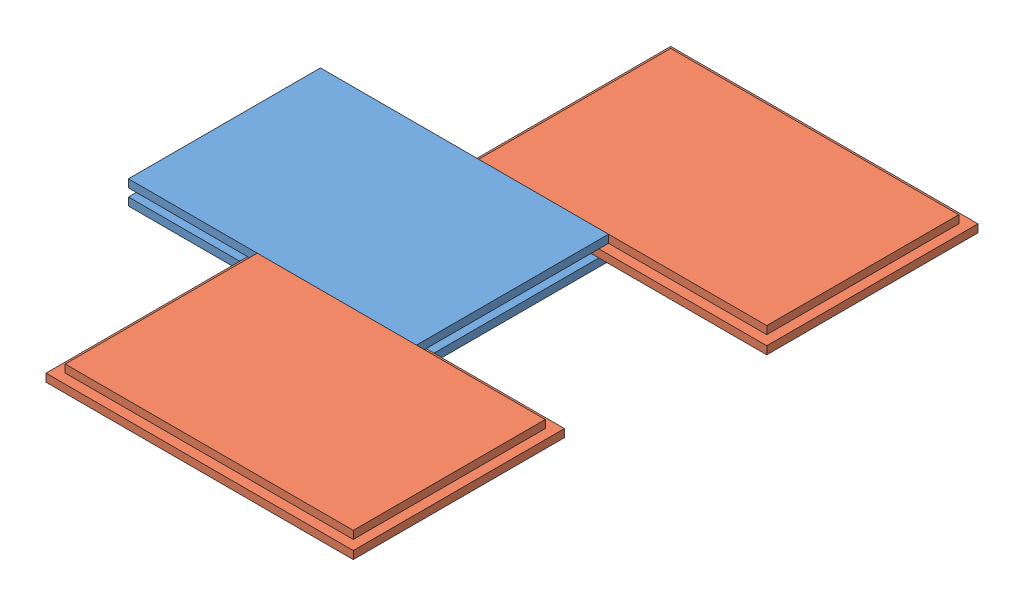
SolidWorks assembly Assem1, configuration Default. Lengths in mm.
Overall size (237.4 12.3 310).
3 component instances, 2 part files, 4 mates.
Components (placement in the parent):
- foto lijst met gleuf concept 1-1: foto lijst met gleuf concept 1 [Default] at (22.8023 87.9306 121.9151) size (150 12.3 100)
- foto lijst met uitstekels concept 1-1: foto lijst met uitstekels concept 1 [Default] at (89.8868 87.9306 221.9151) size (160 12.3 110)
- foto lijst met uitstekels concept 1-2: foto lijst met uitstekels concept 1 [Default] at (105.2056 87.9306 21.9151) size (160 12.3 110)
Mates (geometry in assembly coordinates):
- Coincident1: coincident: plane of foto lijst met gleuf concept 1-1 through (22.8023 96.1306 121.9151) normal (0 -1 0); plane of foto lijst met uitstekels concept 1-1 through (89.8868 96.1306 221.9151) normal (0 1 0)
- Coincident2: coincident: plane of foto lijst met gleuf concept 1-1 through (-52.1977 100.2306 171.9151) normal (0 0 1); plane of foto lijst met uitstekels concept 1-1 through (14.8868 100.2306 171.9151) normal (0 0 -1)
- Coincident3: coincident: plane of foto lijst met gleuf concept 1-1 through (22.8023 96.1306 121.9151) normal (0 -1 0); plane of foto lijst met uitstekels concept 1-2 through (105.2056 96.1306 -21.7363) normal (0 1 0)
- Coincident4: coincident: plane of foto lijst met gleuf concept 1-1 through (-52.1977 100.2306 71.9151) normal (0 0 -1); plane of foto lijst met uitstekels concept 1-2 through (30.2056 100.2306 71.9151) normal (0 0 1)
